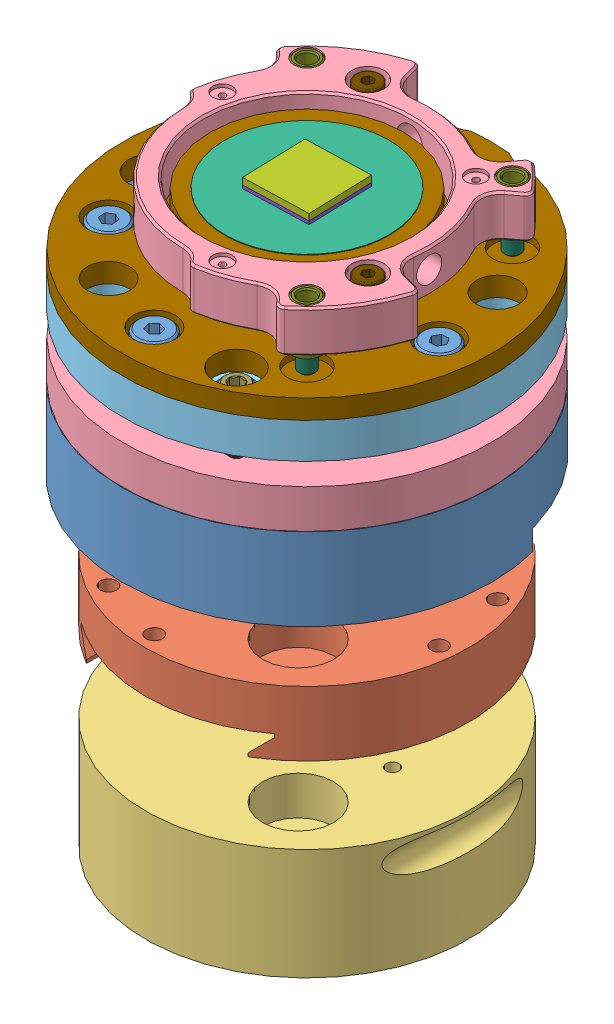
SolidWorks assembly IFX_Sample_Holder_V2, configuration Standard. Lengths in mm.
Overall size (57.15 103.64 57.15).
67 component instances, 22 part files, 85 mates.
Components (placement in the parent):
- BottomPlate_V2-1: BottomPlate_V2 [Standard] at (0 -6 0) x (1 0 0) z (0 0 -1) size (57.15 12.7 57.15)
- Zeiss_Aufnahme_V2-1: Zeiss_Aufnahme_V2 [Standard] at (0 -39.2611 0) x (0 1 0) z (1 0 0) size (10 44 50)
- Prisfix_Nano_Palette_Nachbau_V2-1: Prisfix_Nano_Palette_Nachbau_V2 [Standard] at (0 -82.1364 0) x (-1 0 0) z (0 -1 0) size (50 50 31)
- ReceivingPlate_V2-1: ReceivingPlate_V2 [Standard] x (0 -1 0) z (0 0 1) size (6 57 57)
- TopPlate_V2-1: TopPlate_V2 [Standard] at (0 8.8963 0) x (0 0 -1) z (-1 0 0) size (57 5.5 57)
- Stub-25-4_V2-1: Stub-25-4_V2 [Standard] at (0 19.9963 0) x (-0.999522 0 0.030921) z (0.030921 0 0.999522) size (25.4 11 25.4)
- Probe_10-10-15_V2-1: Probe_10-10-15_V2 [Standard] at (0 19.9963 0) x (0 1 0) z (0.030921 0 0.999522) size (1.5 10 10)
- Probe_10-10-05_V2-1: Probe_10-10-05_V2 [Standard] at (0 19.9963 0) x (0 1 0) z (0.030921 0 0.999522) size (0.5 10 10)
- Aufnahme_Stub-25-4_V2-1: Aufnahme_Stub-25-4_V2 [Standard] at (0 8.8963 0) x (1 0 0) z (0 -1 0) size (57 57 11)
- SteelBall_V2-1: SteelBall_V2 [Standard] at (10.6066 1.6963 -10.6066) x (0 -1 0) z (-0.834138 0 0.551556) size (6 6 6)
- F4MSSN1P-Solidworks_V2-1: F4MSSN1P-Solidworks_V2 [Default] at (10.6066 6.3902 21.5291) size (5.99 5 5.99)
- F4MSS10-Solidworks_V2-1: F4MSS10-Solidworks_V2 [Default] at (28.9171 56.4909 7.775) x (0 1 0) z (-0.546944 0 0.837169) size (10.11 4 4)
- F4MSSN1P-Solidworks_V2-2: F4MSSN1P-Solidworks_V2 [Default] at (-21.5291 6.3902 -10.6066) x (0.978437 0 0.206545) z (-0.206545 0 0.978437) size (5.99 5 5.99)
- F4MSS10-Solidworks_V2-2: F4MSS10-Solidworks_V2 [Default] at (-6.1386 56.4909 -27.5649) x (0 1 0) z (-0.379375 0 0.925243) size (10.11 4 4)
- CJPBPA2_3_00_V2-1: CJPBPA2_3_00_V2 [Default] at (13.25 8.8963 0) x (0 1 0) z (-0.018566 0 0.999828) size (8 3 3)
- CJPBPD2_3_00_V2-1: CJPBPD2_3_00_V2 [Default] at (-13.25 8.8963 0) x (0 1 0) z (0.147731 0 -0.989028) size (8 3 2.79)
- F2D5ES8-Solidworks_V2-1: F2D5ES8-Solidworks_V2 [Default] at (-15.9099 15.1889 -15.9099) x (-0.732448 0 -0.680823) z (0 -1 0) size (2.5 2.5 8.06)
- F2D5ESN1P-Solidworks_V2-1: F2D5ESN1P-Solidworks_V2 [Default] at (-15.9099 17.9935 -15.9099) x (0.999346 0 -0.036156) z (0.036156 0 0.999346) size (4.5 7.01 4.5)
- CJPBPA2_3_00_V2-2: CJPBPA2_3_00_V2 [Default] at (-13.25 -6 0) x (0 1 0) z (0.972202 0 0.234145) size (8 3 3)
- CJPBPD2_3_00_V2-2: CJPBPD2_3_00_V2 [Default] at (13.25 -6 0) x (0 1 0) z (0.983044 0 0.183369) size (8 3 2.79)
- Disc_Spring_Package_5_V2-1: Disc_Spring_Package_5_V2 [Standard] at (10.6066 -2.4 11.9791) x (0.547029 0 -0.837114) z (-0.837114 0 -0.547029) size (10 6.3 10)
  - 07360_050_V2-1: 07360_050_V2 [Default] at origin size (10 0.7 10)
  - 07360_050_V2-2: 07360_050_V2 [Default] at (0 1.4 0) x (-1 0 0) z (0 0 1) size (10 0.7 10)
  - 07360_050_V2-3: 07360_050_V2 [Default] at (0 1.4 0) size (10 0.7 10)
  - 07360_050_V2-4: 07360_050_V2 [Default] at (0 2.8 0) x (-1 0 0) z (0 0 1) size (10 0.7 10)
  - 07360_050_V2-5: 07360_050_V2 [Default] at (0 2.8 0) x (-1 0 0) z (0 0 -1) size (10 0.7 10)
  - 07360_050_V2-6: 07360_050_V2 [Default] at (0 4.2 0) x (-1 0 0) z (0 0 1) size (10 0.7 10)
  - 07360_050_V2-7: 07360_050_V2 [Default] at (0 4.2 0) size (10 0.7 10)
  - 07360_050_V2-8: 07360_050_V2 [Default] x (1 0 0) z (0 0 -1) size (10 0.7 10)
  - 07360_050_V2-9: 07360_050_V2 [Default] at (0 -1.4 0) size (10 0.7 10)
- Disc_Spring_Package_5_V2-2: Disc_Spring_Package_5_V2 [Standard] at (-11.9791 -2.4 -10.6066) x (0.668609 0 0.743614) z (0.743614 0 -0.668609) size (10 6.3 10)
  - 07360_050_V2-1: 07360_050_V2 [Default] at origin size (10 0.7 10)
  - 07360_050_V2-2: 07360_050_V2 [Default] at (0 1.4 0) x (-1 0 0) z (0 0 1) size (10 0.7 10)
  - 07360_050_V2-3: 07360_050_V2 [Default] at (0 1.4 0) size (10 0.7 10)
  - 07360_050_V2-4: 07360_050_V2 [Default] at (0 2.8 0) x (-1 0 0) z (0 0 1) size (10 0.7 10)
  - 07360_050_V2-5: 07360_050_V2 [Default] at (0 2.8 0) x (-1 0 0) z (0 0 -1) size (10 0.7 10)
  - 07360_050_V2-6: 07360_050_V2 [Default] at (0 4.2 0) x (-1 0 0) z (0 0 1) size (10 0.7 10)
  - 07360_050_V2-7: 07360_050_V2 [Default] at (0 4.2 0) size (10 0.7 10)
  - 07360_050_V2-8: 07360_050_V2 [Default] x (1 0 0) z (0 0 -1) size (10 0.7 10)
  - 07360_050_V2-9: 07360_050_V2 [Default] at (0 -1.4 0) size (10 0.7 10)
- schraube_iso_4762-m2x10_V2-1: schraube_iso_4762-m2x10_V2 [Default] at (-8.2411 19.3963 -17.673) x (0.432728 0 -0.901524) z (0 1 0) size (3.8 3.8 12)
- SLHS-M3-6-1: SLHS-M3-6 [Standard] at (-19.4856 9.6963 11.25) x (0 -1 0) z (-0.996714 0 0.081006) size (8 5.5 5.5)
- CSHBT-SUS-M4-14-1: CSHBT-SUS-M4-14 [CSHBT-SUS-M4-14] at (10.6066 -7.3 11.9791) x (1 0 0) z (0 -1 0) size (7.5 7.5 16.6)
- CSHBT-SUS-M4-14-2: CSHBT-SUS-M4-14 [CSHBT-SUS-M4-14] at (-11.9791 -7.3 -10.6066) x (1 0 0) z (0 -1 0) size (7.5 7.5 16.6)
- Tellerfederpaket_0B0187-010-S(LE=0.38)_V2-1: Tellerfederpaket_0B0187-010-S(LE=0.38)_V2 [Standard] at (-8.2411 17.4963 -17.673) x (0 1 0) z (-0.546944 0 0.837169) size (1.9 6.2 6.2)
  - 0B0187-010-S(LE=0.38)-1: 0B0187-010-S(LE=0.38) [Standard] at origin size (0.38 4.75 4.75)
  - 0B0187-010-S(LE=0.38)-2: 0B0187-010-S(LE=0.38) [Standard] at (0.76 0 0) x (-1 0 0) z (0 -0.924225 -0.381849) size (0.38 4.75 4.75)
  - 0B0187-010-S(LE=0.38)-3: 0B0187-010-S(LE=0.38) [Standard] at (0.76 0 0) size (0.38 4.75 4.75)
  - 0B0187-010-S(LE=0.38)-4: 0B0187-010-S(LE=0.38) [Standard] at (1.52 0 0) x (-1 0 0) z (0 -0.924225 -0.381849) size (0.38 4.75 4.75)
  - 0B0187-010-S(LE=0.38)-5: 0B0187-010-S(LE=0.38) [Standard] at (1.52 0 0) x (1 0 0) z (0 -0.028319 0.999599) size (0.38 4.75 4.75)
- Adjusting-Nut_Stub-25-4_orthogonal_V2-1: Adjusting-Nut_Stub-25-4_orthogonal_V2 [Standard] at (0 14.9963 0) x (1 0 0) z (0 -1 0) size (44.66 44.66 6.5)
- SLHS-M3-6-5: SLHS-M3-6 [Standard] at (-22.4144 -3.5 1.961) x (0 -1 0) z (-0.882189 0 0.470896) size (8 5.5 5.5)
- F2D5ESN1P-Solidworks_V2-4: F2D5ESN1P-Solidworks_V2 [Default] at (15.9099 17.9935 -15.9099) x (0.949265 0 0.314476) z (-0.314476 0 0.949265) size (4.5 7.01 4.5)
- F2D5ESN1P-Solidworks_V2-5: F2D5ESN1P-Solidworks_V2 [Default] at (15.9099 17.9935 15.9099) x (0.999877 0 0.015662) z (-0.015662 0 0.999877) size (4.5 7.01 4.5)
- F2D5ES8-Solidworks_V2-4: F2D5ES8-Solidworks_V2 [Default] at (15.9099 15.1889 -15.9099) x (-0.847628 0 -0.53059) z (0 -1 0) size (2.5 2.5 8.06)
- F2D5ES8-Solidworks_V2-5: F2D5ES8-Solidworks_V2 [Default] at (15.9099 15.1889 15.9099) x (-0.94208 0 -0.335389) z (0 -1 0) size (2.5 2.5 8.06)
- schraube_iso_4762-m2x10_V2-2: schraube_iso_4762-m2x10_V2 [Default] at (17.673 19.3963 8.2411) x (-0.480373 0 -0.877065) z (0 1 0) size (3.8 3.8 12)
- Tellerfederpaket_0B0187-010-S(LE=0.38)_V2-2: Tellerfederpaket_0B0187-010-S(LE=0.38)_V2 [Standard] at (17.673 17.4963 8.2411) x (0 1 0) z (-0.805188 0 0.59302) size (1.9 6.2 6.2)
  - 0B0187-010-S(LE=0.38)-1: 0B0187-010-S(LE=0.38) [Standard] at origin size (0.38 4.75 4.75)
  - 0B0187-010-S(LE=0.38)-2: 0B0187-010-S(LE=0.38) [Standard] at (0.76 0 0) x (-1 0 0) z (0 -0.924225 -0.381849) size (0.38 4.75 4.75)
  - 0B0187-010-S(LE=0.38)-3: 0B0187-010-S(LE=0.38) [Standard] at (0.76 0 0) size (0.38 4.75 4.75)
  - 0B0187-010-S(LE=0.38)-4: 0B0187-010-S(LE=0.38) [Standard] at (1.52 0 0) x (-1 0 0) z (0 -0.924225 -0.381849) size (0.38 4.75 4.75)
  - 0B0187-010-S(LE=0.38)-5: 0B0187-010-S(LE=0.38) [Standard] at (1.52 0 0) x (1 0 0) z (0 -0.028319 0.999599) size (0.38 4.75 4.75)
- SLHS-M3-6-9: SLHS-M3-6 [Standard] at (22.4144 9.6963 1.961) x (0 -1 0) z (0.034519 0 0.999404) size (8 5.5 5.5)
- SLHS-M3-6-10: SLHS-M3-6 [Standard] at (-1.1776 9.6963 22.4692) x (0 -1 0) z (-0.963862 0 0.266402) size (8 5.5 5.5)
- SLHS-M3-6-11: SLHS-M3-6 [Standard] at (20.7114 -3.5 -8.7915) x (0 -1 0) z (0.292605 0 0.956233) size (8 5.5 5.5)
- SLHS-M3-6-12: SLHS-M3-6 [Standard] at (-11.25 -3.5 19.4856) x (0 -1 0) z (0.74144 0 -0.671019) size (8 5.5 5.5)
Mates (geometry in assembly coordinates):
- Deckungsgleich24: coincident aligned: plane of ReceivingPlate_V2-1 through (0 0 0) normal (0 0 1); plane of assembly through (0 0 0) normal (0 0 1)
- Konzentrisch18: concentric aligned: cylinder of ReceivingPlate_V2-1 through (0 -6 0) axis (0 1 0) radius 28.5; cylinder of BottomPlate_V2-1 through (0 -18.7 0) axis (0 1 0) radius 28.575
- Konzentrisch20: concentric aligned: cylinder of ReceivingPlate_V2-1 through (0 -6 0) axis (0 1 0) radius 28.5; cylinder of TopPlate_V2-1 through (0 3.3963 0) axis (0 1 0) radius 28.5
- Konzentrisch25: concentric anti-aligned: cylinder of ReceivingPlate_V2-1 through (0 -6 0) axis (0 1 0) radius 28.5; cylinder of Zeiss_Aufnahme_V2-1 through (0 -29.2611 0) axis (0 -1 0) radius 25
- Deckungsgleich31: coincident aligned: plane of ReceivingPlate_V2-1 through (0 0 0) normal (1 0 0); plane of assembly through (0 0 0) normal (1 0 0)
- Deckungsgleich32: coincident anti-aligned: plane of ReceivingPlate_V2-1 through (0 0 0) normal (0 -1 0); plane of assembly through (0 0 0) normal (0 1 0)
- Abstand7: distance = 1.9 mm anti-aligned: plane of SteelBall_V2-1 through (10.6066 1.6963 -10.6066) normal (0 -1 0); plane of ReceivingPlate_V2-1 through (0 0 0) normal (0 1 0)
- Abstand8: distance = 1.7 mm aligned: plane of SteelBall_V2-1 through (10.6066 1.6963 -10.6066) normal (0 -1 0); plane of TopPlate_V2-1 through (0 3.3963 0) normal (0 -1 0)
- Konzentrisch31: concentric anti-aligned: cylinder of ReceivingPlate_V2-1 through (0 -6 0) axis (0 1 0) radius 28.5; cylinder of Prisfix_Nano_Palette_Nachbau_V2-1 through (0 -82.1364 0) axis (0 -1 0) radius 25
- Konzentrisch33: concentric anti-aligned: cylinder of Stub-25-4_V2-1 through (0 16.9963 0) axis (0 1 0) radius 12.7; cylinder of Aufnahme_Stub-25-4_V2-1 through (0 8.8963 0) axis (0 -1 0) radius 12.7
- Deckungsgleich38: coincident anti-aligned: plane of Stub-25-4_V2-1 through (0 16.9963 0) normal (0 -1 0); plane of Aufnahme_Stub-25-4_V2-1 through (0 16.9963 12.7) normal (0 1 0)
- Deckungsgleich39: coincident anti-aligned: plane of Stub-25-4_V2-1 through (0 19.9963 0) normal (0 1 0); plane of Probe_10-10-15_V2-1 through (0 19.9963 0) normal (0 -1 0)
- Deckungsgleich40: coincident anti-aligned: plane of Stub-25-4_V2-1 through (0 19.9963 0) normal (0 1 0); plane of Probe_10-10-05_V2-1 through (0 19.9963 0) normal (0 -1 0)
- Konzentrisch35: concentric anti-aligned: cylinder of Stub-25-4_V2-1 through (0 8.9963 0) axis (0 1 0) radius 1.6
- Deckungsgleich42: coincident aligned: plane of Stub-25-4_V2-1 through (0 19.9963 0) normal (0.030921 0 0.999522); plane of Probe_10-10-15_V2-1 through (0 19.9963 0) normal (0.030921 0 0.999522)
- Deckungsgleich43: coincident aligned: plane of Stub-25-4_V2-1 through (0 19.9963 0) normal (0.030921 0 0.999522); plane of Probe_10-10-05_V2-1 through (0 19.9963 0) normal (0.030921 0 0.999522)
- Deckungsgleich45: coincident aligned: plane of Stub-25-4_V2-1 through (0 19.9963 0) normal (-0.999522 0 0.030921); plane of Probe_10-10-15_V2-1 through (0 19.9963 0) normal (-0.999522 0 0.030921)
- Deckungsgleich46: coincident aligned: plane of Stub-25-4_V2-1 through (0 19.9963 0) normal (-0.999522 0 0.030921); plane of Probe_10-10-05_V2-1 through (0 19.9963 0) normal (-0.999522 0 0.030921)
- Konzentrisch38: concentric anti-aligned: cylinder of F4MSSN1P-Solidworks_V2-1 through (10.6066 8.8921 21.5291) axis (0 1 0) radius 2.7495; cylinder of TopPlate_V2-1 through (10.6066 4.3963 21.5291) axis (0 -1 0) radius 3.05
- Deckungsgleich52: coincident anti-aligned: plane of F4MSSN1P-Solidworks_V2-1 through (10.6066 4.3963 21.5291) normal (0 1 0); plane of TopPlate_V2-1 through (10.6066 4.3963 21.5291) normal (0 -1 0)
- Konzentrisch39: concentric anti-aligned: cylinder of F4MSSN1P-Solidworks_V2-1 through (10.6066 8.8921 21.5291) axis (0 1 0) radius 2; cylinder of F4MSS10-Solidworks_V2-1 through (10.6066 3.3535 21.5291) axis (0 -1 0) radius 2
- Tangential9: tangent anti-aligned: plane of ReceivingPlate_V2-1 through (0 0 0) normal (0 1 0); sphere of F4MSS10-Solidworks_V2-1
- Konzentrisch52: concentric anti-aligned: cylinder of F4MSSN1P-Solidworks_V2-2 through (-21.5291 8.8921 -10.6066) axis (0 1 0) radius 2.7495; cylinder of TopPlate_V2-1 through (-21.5291 4.3963 -10.6066) axis (0 -1 0) radius 3.05
- Deckungsgleich61: coincident anti-aligned: plane of F4MSSN1P-Solidworks_V2-2 through (-21.5291 4.3963 -10.6066) normal (0 1 0); plane of TopPlate_V2-1 through (-21.5291 4.3963 -10.6066) normal (0 -1 0)
- Konzentrisch53: concentric anti-aligned: cylinder of F4MSSN1P-Solidworks_V2-2 through (-21.5291 8.8921 -10.6066) axis (0 1 0) radius 2; cylinder of F4MSS10-Solidworks_V2-2 through (-21.5291 3.3535 -10.6066) axis (0 -1 0) radius 2
- Tangential10: tangent anti-aligned: plane of ReceivingPlate_V2-1 through (0 0 0) normal (0 1 0); sphere of F4MSS10-Solidworks_V2-2
- Deckungsgleich74: coincident anti-aligned: plane of ReceivingPlate_V2-1 through (0 -6 0) normal (0 -1 0); plane of BottomPlate_V2-1 through (0 -6 0) normal (0 1 0)
- Konzentrisch68: concentric anti-aligned: circle of ReceivingPlate_V2-1; circle of Disc_Spring_Package_5_V2-1/07360_050_V2-1
- Deckungsgleich76: coincident anti-aligned: plane of ReceivingPlate_V2-1 through (12.8566 -1 11.9791) normal (0 -1 0); circle of Disc_Spring_Package_5_V2-1/07360_050_V2-9
- Deckungsgleich77: coincident anti-aligned: plane of ReceivingPlate_V2-1 through (-9.7291 -1 -10.6066) normal (0 -1 0); circle of Disc_Spring_Package_5_V2-2/07360_050_V2-9
- Deckungsgleich79: coincident anti-aligned: plane of TopPlate_V2-1 through (0 8.8963 0) normal (0 1 0); plane of Aufnahme_Stub-25-4_V2-1 through (0 8.8963 28.5) normal (0 -1 0)
- Deckungsgleich80: coincident aligned: plane of Aufnahme_Stub-25-4_V2-1 through (0 8.8963 0) normal (1 0 0); plane of assembly through (0 0 0) normal (1 0 0)
- Konzentrisch74: concentric anti-aligned: cylinder of F2D5ES8-Solidworks_V2-1 through (-15.9099 12.707 -15.9099) axis (0 -1 0) radius 1.25; cylinder of F2D5ESN1P-Solidworks_V2-1 through (-15.9099 21.4987 -15.9099) axis (0 1 0) radius 1.25
- Tangential11: tangent anti-aligned: sphere of F2D5ES8-Solidworks_V2-1; plane of Aufnahme_Stub-25-4_V2-1 through (-15.9099 10.8963 -15.9099) normal (0 1 0)
- Deckungsgleich85: coincident aligned: plane of BottomPlate_V2-1 through (0 -6 0) normal (1 0 0); plane of assembly through (0 0 0) normal (1 0 0)
- Deckungsgleich88: coincident aligned: plane of Zeiss_Aufnahme_V2-1 through (0 -39.2611 0) normal (1 0 0); plane of assembly through (0 0 0) normal (1 0 0)
- Senkrecht1: perpendicular: plane of TopPlate_V2-1 through (0 8.8963 -10.6066) normal (0 0 -1); plane of assembly through (0 0 0) normal (1 0 0)
- Deckungsgleich90: coincident anti-aligned: line of TopPlate_V2-1 through (10.6066 22.9405 -10.6066) axis (0 -1 0); line of SteelBall_V2-1 through (10.6066 -1.8787 -10.6066) axis (0 1 0)
- Deckungsgleich91: coincident anti-aligned: plane of Prisfix_Nano_Palette_Nachbau_V2-1 through (0 -82.1364 0) normal (-1 0 0); plane of assembly through (0 0 0) normal (1 0 0)
- Tangential12: tangent aligned: cone of ReceivingPlate_V2-1 through (10.6066 -0.001 -10.6066) axis (0 -1 0); unknown of SteelBall_V2-1
- Konzentrisch79: concentric anti-aligned: cylinder of ReceivingPlate_V2-1 through (-13.25 -6 0) axis (0 -1 0) radius 1.5; cylinder of CJPBPA2_3_00_V2-2 through (-13.25 -2 0) axis (0 1 0) radius 1
- Deckungsgleich96: coincident aligned: plane of ReceivingPlate_V2-1 through (0 -6 0) normal (0 -1 0); plane of CJPBPA2_3_00_V2-2 through (-13.5193 -6 1.118) normal (0 -1 0)
- Konzentrisch80: concentric anti-aligned: cylinder of ReceivingPlate_V2-1 through (13.25 -6 0) axis (0 -1 0) radius 1.5; cylinder of CJPBPD2_3_00_V2-2 through (13.25 -2 0) axis (0 1 0) radius 1
- Deckungsgleich97: coincident aligned: plane of ReceivingPlate_V2-1 through (0 -6 0) normal (0 -1 0); plane of CJPBPD2_3_00_V2-2 through (13.0391 -6 1.1305) normal (0 -1 0)
- Konzentrisch82: concentric anti-aligned: cylinder of Aufnahme_Stub-25-4_V2-1 through (-13.25 8.8963 0) axis (0 -1 0) radius 1.5; cylinder of CJPBPD2_3_00_V2-1 through (-13.25 12.8963 0) axis (0 1 0) radius 1
- Deckungsgleich98: coincident aligned: plane of Aufnahme_Stub-25-4_V2-1 through (0 8.8963 28.5) normal (0 -1 0); plane of CJPBPD2_3_00_V2-1 through (-12.1126 8.8963 0.1699) normal (0 -1 0)
- Konzentrisch83: concentric anti-aligned: cylinder of Aufnahme_Stub-25-4_V2-1 through (13.25 8.8963 0) axis (0 -1 0) radius 1.5; cylinder of CJPBPA2_3_00_V2-1 through (13.25 12.8963 0) axis (0 1 0) radius 1
- Deckungsgleich99: coincident aligned: plane of Aufnahme_Stub-25-4_V2-1 through (0 8.8963 28.5) normal (0 -1 0); plane of CJPBPA2_3_00_V2-1 through (12.1002 8.8963 -0.0214) normal (0 -1 0)
- Deckungsgleich102: coincident aligned: plane of schraube_iso_4762-m2x10_V2-1 through (-9.5933 19.3963 -18.3221) normal (0 -1 0); circle of Tellerfederpaket_0B0187-010-S(LE=0.38)_V2-1/0B0187-010-S(LE=0.38)-5
- Konzentrisch87: concentric aligned: cylinder of Aufnahme_Stub-25-4_V2-1 through (0 8.8963 0) axis (0 -1 0) radius 15; cylinder of Adjusting-Nut_Stub-25-4_orthogonal_V2-1 through (0 14.9963 0) axis (0 -1 0) radius 16
- Deckungsgleich103: coincident aligned: plane of Probe_10-10-15_V2-1 through (0 21.4963 0) normal (0 1 0); plane of Adjusting-Nut_Stub-25-4_orthogonal_V2-1 through (0 21.4963 25) normal (0 1 0)
- Deckungsgleich104: coincident aligned: plane of Adjusting-Nut_Stub-25-4_orthogonal_V2-1 through (0 14.9963 0) normal (0 0 1); plane of assembly through (0 0 0) normal (0 0 1)
- Konzentrisch88: concentric aligned: cylinder of F2D5ESN1P-Solidworks_V2-1 through (-15.9099 21.4987 -15.9099) axis (0 1 0) radius 2.0002; cylinder of Adjusting-Nut_Stub-25-4_orthogonal_V2-1 through (-15.9099 21.4963 -15.9099) axis (0 1 0) radius 2
- Deckungsgleich105: coincident anti-aligned: plane of F2D5ESN1P-Solidworks_V2-1 through (-14.7867 14.9963 -15.9505) normal (0 1 0); plane of Adjusting-Nut_Stub-25-4_orthogonal_V2-1 through (0 14.9963 25) normal (0 -1 0)
- Konzentrisch89: concentric aligned: cylinder of schraube_iso_4762-m2x10_V2-1 through (-8.2411 14.3213 -17.673) axis (0 1 0) radius 1; cylinder of Tellerfederpaket_0B0187-010-S(LE=0.38)_V2-1/0B0187-010-S(LE=0.38)-5 through (-8.2411 19.3963 -17.673) axis (0 1 0) radius 1.18
- Konzentrisch90: concentric aligned: cylinder of schraube_iso_4762-m2x10_V2-1 through (-8.2411 14.3213 -17.673) axis (0 1 0) radius 1; cylinder of Adjusting-Nut_Stub-25-4_orthogonal_V2-1 through (-8.2411 21.4963 -17.673) axis (0 1 0) radius 1.1
- Deckungsgleich106: coincident aligned: circle of Tellerfederpaket_0B0187-010-S(LE=0.38)_V2-1/0B0187-010-S(LE=0.38)-1; plane of Adjusting-Nut_Stub-25-4_orthogonal_V2-1 through (-7.1411 17.4963 -17.673) normal (0 1 0)
- Konzentrisch91: concentric anti-aligned: cylinder of SLHS-M3-6-1 through (-19.4856 3.6963 11.25) axis (0 -1 0) radius 1.5; cylinder of Aufnahme_Stub-25-4_V2-1 through (-19.4856 11.8963 11.25) axis (0 1 0) radius 1.7
- Deckungsgleich107: coincident anti-aligned: plane of Aufnahme_Stub-25-4_V2-1 through (-17.7856 9.6963 11.25) normal (0 1 0); plane of SLHS-M3-6-1 through (-19.2628 9.6963 13.991) normal (0 -1 0)
- Konzentrisch92: concentric anti-aligned: cylinder of SLHS-M3-6-5 through (-22.4144 -9.5 1.961) axis (0 -1 0) radius 1.5; cylinder of ReceivingPlate_V2-1 through (-22.4144 0 1.961) axis (0 1 0) radius 1.7
- Deckungsgleich108: coincident anti-aligned: plane of ReceivingPlate_V2-1 through (-20.7144 -3.5 1.961) normal (0 1 0); plane of SLHS-M3-6-5 through (-21.1194 -3.5 4.387) normal (0 -1 0)
- Konzentrisch93: concentric aligned: cylinder of Adjusting-Nut_Stub-25-4_orthogonal_V2-1 through (15.9099 21.4963 -15.9099) axis (0 1 0) radius 2; cylinder of F2D5ESN1P-Solidworks_V2-4 through (15.9099 21.4987 -15.9099) axis (0 1 0) radius 2.0002
- Deckungsgleich109: coincident anti-aligned: plane of Adjusting-Nut_Stub-25-4_orthogonal_V2-1 through (0 14.9963 25) normal (0 -1 0); plane of F2D5ESN1P-Solidworks_V2-4 through (16.9768 14.9963 -15.5564) normal (0 1 0)
- Konzentrisch94: concentric aligned: cylinder of Adjusting-Nut_Stub-25-4_orthogonal_V2-1 through (15.9099 21.4963 15.9099) axis (0 1 0) radius 2; cylinder of F2D5ESN1P-Solidworks_V2-5 through (15.9099 21.4987 15.9099) axis (0 1 0) radius 2.0002
- Deckungsgleich110: coincident anti-aligned: plane of Adjusting-Nut_Stub-25-4_orthogonal_V2-1 through (0 14.9963 25) normal (0 -1 0); plane of F2D5ESN1P-Solidworks_V2-5 through (17.0337 14.9963 15.9275) normal (0 1 0)
- Konzentrisch95: concentric anti-aligned: cylinder of F2D5ESN1P-Solidworks_V2-4 through (15.9099 21.4987 -15.9099) axis (0 1 0) radius 1.25; cylinder of F2D5ES8-Solidworks_V2-4 through (15.9099 12.707 -15.9099) axis (0 -1 0) radius 1.25
- Tangential13: tangent anti-aligned: sphere of F2D5ES8-Solidworks_V2-4; plane of Aufnahme_Stub-25-4_V2-1 through (15.9099 10.8963 -15.9099) normal (0 1 0)
- Tangential14: tangent anti-aligned: sphere of F2D5ES8-Solidworks_V2-5; plane of Aufnahme_Stub-25-4_V2-1 through (15.9099 10.8963 15.9099) normal (0 1 0)
- Konzentrisch96: concentric anti-aligned: cylinder of F2D5ESN1P-Solidworks_V2-5 through (15.9099 21.4987 15.9099) axis (0 1 0) radius 1.25; cylinder of F2D5ES8-Solidworks_V2-5 through (15.9099 12.707 15.9099) axis (0 -1 0) radius 1.25
- Konzentrisch97: concentric aligned: cylinder of Adjusting-Nut_Stub-25-4_orthogonal_V2-1 through (17.673 21.4963 8.2411) axis (0 1 0) radius 1.1; cylinder of schraube_iso_4762-m2x10_V2-2 through (17.673 14.3213 8.2411) axis (0 1 0) radius 1
- Konzentrisch98: concentric aligned: cylinder of Adjusting-Nut_Stub-25-4_orthogonal_V2-1 through (17.673 21.4963 8.2411) axis (0 1 0) radius 2.5; cylinder of Tellerfederpaket_0B0187-010-S(LE=0.38)_V2-2/0B0187-010-S(LE=0.38)-1 through (17.673 17.8763 8.2411) axis (0 1 0) radius 1.18
- Deckungsgleich111: coincident aligned: plane of Adjusting-Nut_Stub-25-4_orthogonal_V2-1 through (18.773 17.4963 8.2411) normal (0 1 0); circle of Tellerfederpaket_0B0187-010-S(LE=0.38)_V2-2/0B0187-010-S(LE=0.38)-1
- Deckungsgleich112: coincident aligned: plane of schraube_iso_4762-m2x10_V2-2 through (16.3574 19.3963 8.9616) normal (0 -1 0); circle of Tellerfederpaket_0B0187-010-S(LE=0.38)_V2-2/0B0187-010-S(LE=0.38)-5
- Concentric1: concentric anti-aligned: cylinder of SLHS-M3-6-9 through (22.4144 3.6963 1.961) axis (0 -1 0) radius 1.5; cylinder of Aufnahme_Stub-25-4_V2-1 through (22.4144 11.8963 1.961) axis (0 1 0) radius 1.7
- Concentric2: concentric anti-aligned: cylinder of SLHS-M3-6-10 through (-1.1776 3.6963 22.4692) axis (0 -1 0) radius 1.5; cylinder of Aufnahme_Stub-25-4_V2-1 through (-1.1776 11.8963 22.4692) axis (0 1 0) radius 1.7
- Coincident1: coincident anti-aligned: plane of Aufnahme_Stub-25-4_V2-1 through (24.1144 9.6963 1.961) normal (0 1 0); plane of SLHS-M3-6-9 through (25.1627 9.6963 1.8661) normal (0 -1 0)
- Coincident2: coincident anti-aligned: plane of Aufnahme_Stub-25-4_V2-1 through (0.5224 9.6963 22.4692) normal (0 1 0); plane of SLHS-M3-6-10 through (-0.445 9.6963 25.1198) normal (0 -1 0)
- Concentric3: concentric anti-aligned: cylinder of SLHS-M3-6-11 through (20.7114 -9.5 -8.7915) axis (0 -1 0) radius 1.5; circle of ReceivingPlate_V2-1
- Concentric4: concentric anti-aligned: cylinder of SLHS-M3-6-12 through (-11.25 -9.5 19.4856) axis (0 -1 0) radius 1.5; cylinder of ReceivingPlate_V2-1 through (-11.25 0 19.4856) axis (0 1 0) radius 1.7
- Coincident3: coincident anti-aligned: plane of ReceivingPlate_V2-1 through (-9.55 -3.5 19.4856) normal (0 1 0); plane of SLHS-M3-6-12 through (-13.0953 -3.5 17.4466) normal (0 -1 0)
- Coincident4: coincident anti-aligned: plane of ReceivingPlate_V2-1 through (22.4114 -3.5 -8.7915) normal (0 1 0); plane of SLHS-M3-6-11 through (23.341 -3.5 -9.5961) normal (0 -1 0)
- Concentric7: concentric anti-aligned: circle of Disc_Spring_Package_5_V2-2/07360_050_V2-9; cylinder of CSHBT-SUS-M4-14-2 through (-11.9791 -22.0719 -10.6066) axis (0 -1 0) radius 2
- Concentric8: concentric anti-aligned: circle of Disc_Spring_Package_5_V2-1/07360_050_V2-9; cylinder of CSHBT-SUS-M4-14-1 through (10.6066 -22.0719 11.9791) axis (0 -1 0) radius 2
- Coincident5: coincident aligned: circle of Disc_Spring_Package_5_V2-1/07360_050_V2-7; plane of CSHBT-SUS-M4-14-1 through (10.6066 -7.3 13.9791) normal (0 1 0)
- Coincident6: coincident aligned: circle of Disc_Spring_Package_5_V2-2/07360_050_V2-7; plane of CSHBT-SUS-M4-14-2 through (-11.9791 -7.3 -8.6066) normal (0 1 0)
